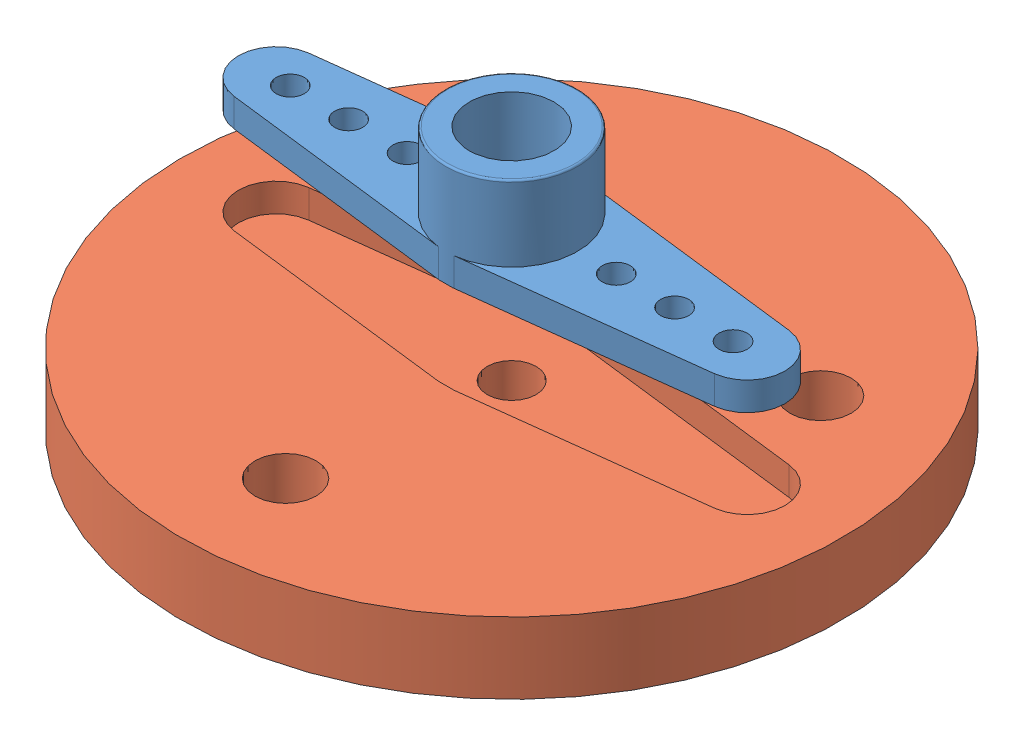
SolidWorks assembly Assem1, configuration Default. Lengths in mm.
Overall size (47.81 13.96 47.81).
2 component instances, 2 part files, 2 mates.
Components (placement in the parent):
- Arm-1: Arm [Default] at (-28.9719 2.0993 0) size (29 5.7 7)
- ServoDiscDef-1: ServoDiscDef [Default] at (-28.9719 -6.363 0) x (-0.866025 0 -0.5) z (0 1 0) size (35 35 3.78)
Mates (geometry in assembly coordinates):
- Concentric1: concentric anti-aligned: cylinder of Arm-1 through (-28.9719 7.5993 0) axis (0 -1 0) radius 1; cylinder of ServoDiscDef-1 through (-28.9719 -6.363 0) axis (0 1 0) radius 1.3
- Coincident1: coincident: plane of Arm-1 through (-28.9719 2.0993 0) normal (0 0 1); line of ServoDiscDef-1 through (14.1 -21.9219 -2.5819) axis (0 -1 0)
